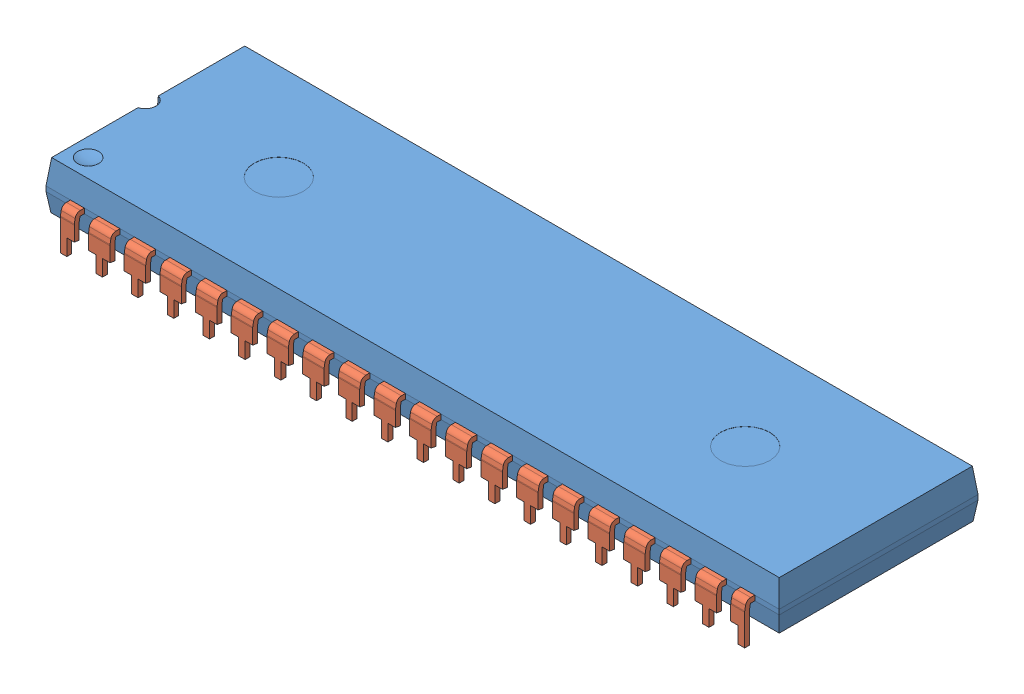
SolidWorks assembly DIP40, configuration Default. Lengths in mm.
Overall size (52.2 4.65 15.59).
3 component instances, 2 part files, 6 mates.
Components (placement in the parent):
- 40DIP_body-1: 40DIP_body [Default] at (-4.6803 3.0616 0.3897) size (52.2 3.4 14.15)
- 40DIP_pins-1: 40DIP_pins [Default] at (-4.6803 2.8866 -5.6853) size (48.72 2.9 1.72)
- 40DIP_pins-2: 40DIP_pins [Default] at (-4.6803 2.8866 6.4647) x (-1 0 0) z (0 0 -1) size (48.72 2.9 1.72)
Mates (geometry in assembly coordinates):
- Coincident1: coincident anti-aligned: plane of 40DIP_pins-2 through (-28.0483 3.0616 6.4647) normal (0 0 -1); plane of 40DIP_body-1 through (-28.0483 2.7116 6.4647) normal (0 0 1)
- Coincident2: coincident anti-aligned: plane of 40DIP_body-1 through (-29.0389 3.0616 6.4647) normal (1 0 0); plane of 40DIP_pins-2 through (-29.0389 3.0616 7.7537) normal (-1 0 0)
- Coincident3: coincident anti-aligned: plane of 40DIP_body-1 through (-29.0389 2.7116 6.4647) normal (0 1 0); plane of 40DIP_pins-2 through (-29.0389 2.7116 7.7537) normal (0 -1 0)
- Coincident4: coincident anti-aligned: plane of 40DIP_body-1 through (-28.0483 2.7116 -5.6853) normal (0 0 -1); plane of 40DIP_pins-1 through (-29.0389 3.0616 -5.6853) normal (0 0 1)
- Coincident5: coincident anti-aligned: plane of 40DIP_body-1 through (-29.0389 3.0616 -5.6853) normal (1 0 0); plane of 40DIP_pins-1 through (-29.0389 3.0616 -6.9743) normal (-1 0 0)
- Coincident6: coincident anti-aligned: plane of 40DIP_body-1 through (-29.0389 2.7116 -5.6853) normal (0 1 0); plane of 40DIP_pins-1 through (-28.0483 2.7116 -6.9743) normal (0 -1 0); sketch_entity of 40DIP_body-1
